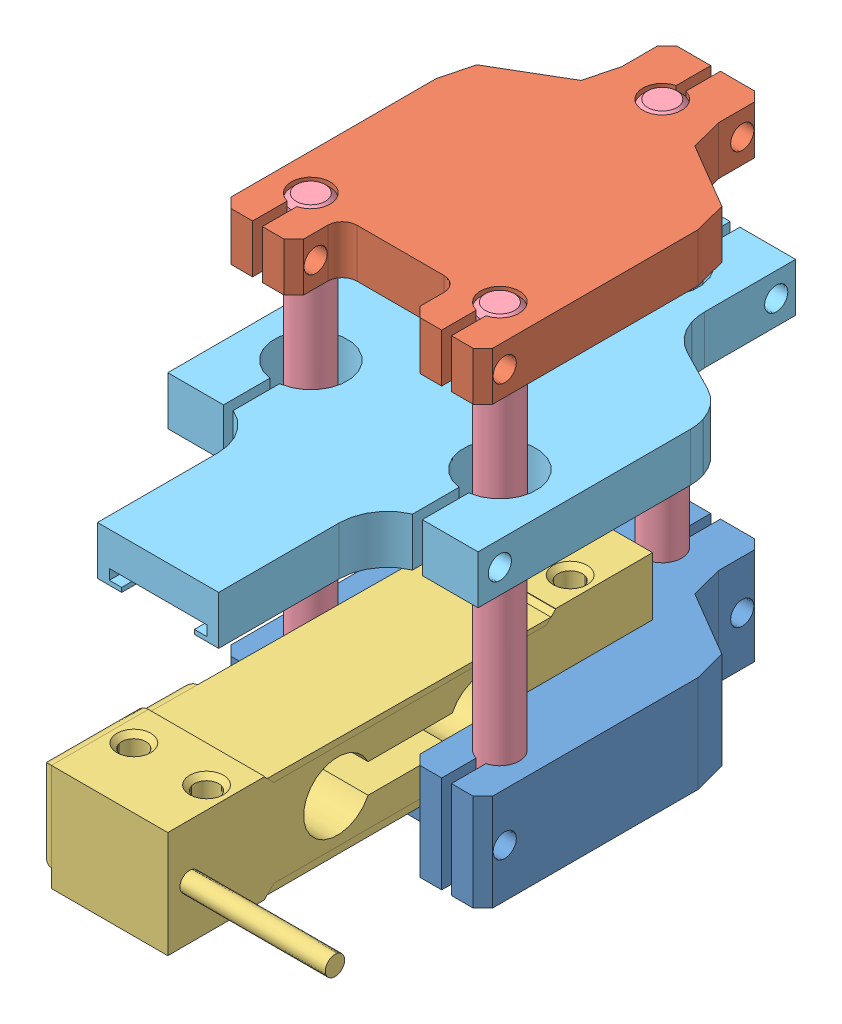
SolidWorks assembly magnet pull force jig, configuration Default. Lengths in mm.
Overall size (74 100 195.8).
7 component instances, 5 part files, 15 mates.
Components (placement in the parent):
- base-1: base [Default] at (-85.1691 2.6841 43.8252) size (54 20 75)
- top-1: top [Default] at (-85.1691 92.6841 43.8252) size (54 10 75)
- weight transducer FNG-1: weight transducer FNG [默认] at (-85.1691 23.6841 73.8252) x (0 0 1) z (-1 0 0) size (166.8 79.61 56.5)
- 8mm rod-1: 8mm rod [Default] at (-65.6691 2.6841 62.8252) x (0.915661 0 0.401952) z (-0.401952 0 0.915661) size (8 100 8)
- 8mm rod-2: 8mm rod [Default] at (-85.1691 2.6841 9.8252) x (0.918785 0 -0.394757) z (0.394757 0 0.918785) size (8 100 8)
- 8mm rod-3: 8mm rod [Default] at (-104.6691 2.6841 62.8252) x (0.884358 0 -0.46681) z (0.46681 0 0.884358) size (8 100 8)
- Slider-1: Slider [Default] at (-85.1691 62.826 44.8252) size (64 10 119)
Mates (geometry in assembly coordinates):
- Coincident1: coincident anti-aligned: plane of base-1 through (-85.1691 12.6841 43.8252) normal (0 1 0); plane of weight transducer FNG-1 through (-97.1691 12.6841 23.8252) normal (0 -1 0)
- Coincident2: coincident anti-aligned: plane of base-1 through (-97.1691 22.6841 23.8252) normal (1 0 0); plane of weight transducer FNG-1 through (-97.1691 23.6841 73.8252) normal (-1 0 0)
- Coincident3: coincident anti-aligned: plane of base-1 through (-73.1691 22.6841 23.8252) normal (0 0 1); plane of weight transducer FNG-1 through (-97.1691 34.6841 23.8252) normal (0 0 -1)
- Concentric1: concentric aligned: cylinder of base-1 through (-65.6691 22.6841 62.8252) axis (0 -1 0) radius 4; cylinder of 8mm rod-1 through (-65.6691 102.6841 62.8252) axis (0 -1 0) radius 4
- Concentric2: concentric aligned: cylinder of base-1 through (-104.6691 22.6841 62.8252) axis (0 -1 0) radius 4; cylinder of 8mm rod-3 through (-104.6691 102.6841 62.8252) axis (0 -1 0) radius 4
- Concentric3: concentric aligned: cylinder of base-1 through (-85.1691 22.6841 9.8252) axis (0 -1 0) radius 4; cylinder of 8mm rod-2 through (-85.1691 102.6841 9.8252) axis (0 -1 0) radius 4
- Concentric4: concentric aligned: cylinder of top-1 through (-65.6691 195.1016 62.8252) axis (0 -1 0) radius 4; cylinder of 8mm rod-1 through (-65.6691 102.6841 62.8252) axis (0 -1 0) radius 4
- Concentric5: concentric aligned: cylinder of top-1 through (-104.6691 195.1016 62.8252) axis (0 -1 0) radius 4; cylinder of 8mm rod-3 through (-104.6691 102.6841 62.8252) axis (0 -1 0) radius 4
- Concentric6: concentric aligned: cylinder of top-1 through (-85.1691 195.1016 9.8252) axis (0 -1 0) radius 4; cylinder of 8mm rod-2 through (-85.1691 102.6841 9.8252) axis (0 -1 0) radius 4
- Coincident9: coincident aligned: plane of top-1 through (-85.1691 102.6841 43.8252) normal (0 1 0); plane of 8mm rod-2 through (-85.1691 102.6841 9.8252) normal (0 1 0)
- Coincident10: coincident aligned: plane of top-1 through (-85.1691 102.6841 43.8252) normal (0 1 0); plane of 8mm rod-1 through (-65.6691 102.6841 62.8252) normal (0 1 0)
- Coincident11: coincident aligned: plane of top-1 through (-85.1691 102.6841 43.8252) normal (0 1 0); plane of 8mm rod-3 through (-104.6691 102.6841 62.8252) normal (0 1 0)
- Coincident12: coincident aligned: circle of base-1; circle of 8mm rod-2
- Concentric10: concentric aligned: cylinder of 8mm rod-2 through (-85.1691 102.6841 9.8252) axis (0 -1 0) radius 4; cylinder of Slider-1 through (-85.1691 179.2262 9.8252) axis (0 -1 0) radius 7.5
- Concentric13: concentric aligned: cylinder of 8mm rod-1 through (-65.6691 102.6841 62.8252) axis (0 -1 0) radius 4; cylinder of Slider-1 through (-65.6691 179.2262 62.8252) axis (0 -1 0) radius 7.5
